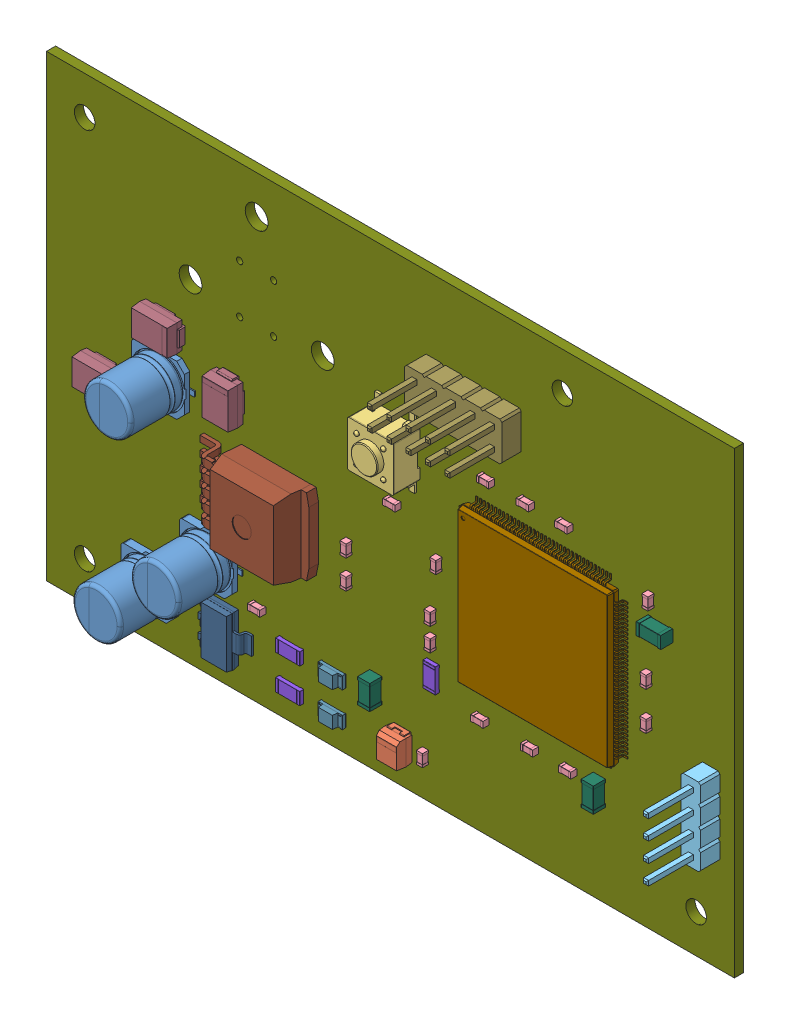
SolidWorks assembly PUTM-G-TM-PCB, configuration Domyślna. Lengths in mm.
Overall size (90 60 11.59).
104 component instances, 17 part files, 0 mates.
Components (placement in the parent):
- TC.step-1: TC.step [Domyślna] at origin size (90 60 11.59)
  - CP_Elec_6.3x7.7.step-1: CP_Elec_6.3x7.7.step [Domyślna] at (126.76 -92.79 1.25) x (-1 0 0) z (0 0 1) size (8.61 8.6 7.7)
    - SOLID.step-1: SOLID.step [Domyślna] at origin size (8.61 8.6 7.7)
  - CP_EIA-3528-21_Kemet-B.step-1: CP_EIA-3528-21_Kemet-B.step [Domyślna] at (159.142 -94.9444 1.25) x (0 -1 0) z (0 0 1) size (3.5 2.8 2.1)
    - SOLID-0.step-1: SOLID-0.step [Domyślna] at origin size (3.5 2.8 2.1)
  - SW_SPST_PTS645.step-1: SW_SPST_PTS645.step [Domyślna] at (158.392 -61.1944 1.25) x (0 -1 0) z (0 0 1) size (9 6 4.3)
    - SOLID-1.step-1: SOLID-1.step [Domyślna] at origin size (9 6 4.3)
  - C_0603_1608Metric.step-1: C_0603_1608Metric.step [Domyślna] at (158.142 -68.1944 1.25) x (-1 0 0) z (0 0 1) size (1.6 0.8 0.8)
    - SOLID-2.step-1: SOLID-2.step [Domyślna] at origin size (1.6 0.8 0.8)
  - PinHeader_1x04_P2.54mm_Vertical.step-1: PinHeader_1x04_P2.54mm_Vertical.step [Domyślna] at (199.392 -86.4444 1.25) x (-1 0 0) z (0 0 1) size (2.54 10.16 11.54)
    - SOLID-3.step-1: SOLID-3.step [Domyślna] at origin size (2.54 10.16 11.54)
  - SOIC-8_3.9x4.9mm_P1.27mm.step-1: SOIC-8_3.9x4.9mm_P1.27mm.step [Domyślna] at (160.892 -62.4444 -0.05) x (-1 0 0) z (0 0 -1) size (6 4.9 1.75)
    - SOLID-4.step-1: SOLID-4.step [Domyślna] at origin size (6 4.9 1.75)
  - TSOT-23.step-1: TSOT-23.step [Domyślna] at (151.892 -62.4444 -0.05) x (-1 0 0) z (0 0 -1) size (2.8 2.9 0.95)
    - SOLID-5.step-1: SOLID-5.step [Domyślna] at origin size (2.8 2.9 0.95)
  - R_1206_3216Metric.step-1: R_1206_3216Metric.step [Domyślna] at (145.892 -62.5444 -0.05) x (0 -1 0) z (0 0 -1) size (3.2 1.6 0.55)
    - SOLID-6.step-1: SOLID-6.step [Domyślna] at origin size (3.2 1.6 0.55)
  - LQFP-144_20x20mm_P0.5mm.step-1: LQFP-144_20x20mm_P0.5mm.step [Domyślna] at (177.642 -73.1944 1.25) size (22 22 1.5)
    - SOLID-7.step-1: SOLID-7.step [Domyślna] at origin size (22 22 1.5)
  - R_1206_3216Metric.step-2: R_1206_3216Metric.step [Domyślna] at (199.642 -64.9444 -0.05) x (-1 0 0) z (0 0 -1) size (3.2 1.6 0.55)
    - SOLID-6.step-1: SOLID-6.step [Domyślna] at origin size (3.2 1.6 0.55)
  - R_1206_3216Metric.step-3: R_1206_3216Metric.step [Domyślna] at (199.642 -67.9444 -0.05) x (-1 0 0) z (0 0 -1) size (3.2 1.6 0.55)
    - SOLID-6.step-1: SOLID-6.step [Domyślna] at origin size (3.2 1.6 0.55)
  - R_1206_3216Metric.step-4: R_1206_3216Metric.step [Domyślna] at (191.392 -56.6944 -0.05) x (-1 0 0) z (0 0 -1) size (3.2 1.6 0.55)
    - SOLID-6.step-1: SOLID-6.step [Domyślna] at origin size (3.2 1.6 0.55)
  - R_1206_3216Metric.step-5: R_1206_3216Metric.step [Domyślna] at (191.392 -47.6944 -0.05) x (-1 0 0) z (0 0 -1) size (3.2 1.6 0.55)
    - SOLID-6.step-1: SOLID-6.step [Domyślna] at origin size (3.2 1.6 0.55)
  - R_1206_3216Metric.step-6: R_1206_3216Metric.step [Domyślna] at (191.392 -50.6944 -0.05) x (-1 0 0) z (0 0 -1) size (3.2 1.6 0.55)
    - SOLID-6.step-1: SOLID-6.step [Domyślna] at origin size (3.2 1.6 0.55)
  - R_1206_3216Metric.step-7: R_1206_3216Metric.step [Domyślna] at (191.392 -53.6944 -0.05) x (-1 0 0) z (0 0 -1) size (3.2 1.6 0.55)
    - SOLID-6.step-1: SOLID-6.step [Domyślna] at origin size (3.2 1.6 0.55)
  - SOT-223.step-1: SOT-223.step [Domyślna] at (136.142 -93.6944 1.25) size (7 6.5 1.7)
    - SOLID-8.step-1: SOLID-8.step [Domyślna] at origin size (7 6.5 1.7)
  - TO-263-5_TabPin3.step-1: TO-263-5_TabPin3.step [Domyślna] at (140.642 -76.6944 1.25) size (15 10 4.42)
    - SOLID-9.step-1: SOLID-9.step [Domyślna] at origin size (15 10 4.42)
  - R_1206_3216Metric.step-8: R_1206_3216Metric.step [Domyślna] at (144.642 -96.1944 1.25) size (3.2 1.6 0.55)
    - SOLID-6.step-1: SOLID-6.step [Domyślna] at origin size (3.2 1.6 0.55)
  - R_1206_3216Metric.step-9: R_1206_3216Metric.step [Domyślna] at (144.642 -91.6944 1.25) x (-1 0 0) z (0 0 1) size (3.2 1.6 0.55)
    - SOLID-6.step-1: SOLID-6.step [Domyślna] at origin size (3.2 1.6 0.55)
  - R_1206_3216Metric.step-10: R_1206_3216Metric.step [Domyślna] at (183.892 -59.6944 -0.05) x (1 0 0) z (0 0 -1) size (3.2 1.6 0.55)
    - SOLID-6.step-1: SOLID-6.step [Domyślna] at origin size (3.2 1.6 0.55)
  - R_1206_3216Metric.step-11: R_1206_3216Metric.step [Domyślna] at (163.142 -85.3444 1.25) x (0 -1 0) z (0 0 1) size (3.2 1.6 0.55)
    - SOLID-6.step-1: SOLID-6.step [Domyślna] at origin size (3.2 1.6 0.55)
  - PinHeader_2x05_P2.54mm_Vertical.step-1: PinHeader_2x05_P2.54mm_Vertical.step [Domyślna] at (173.392 -50.6944 1.25) x (0 -1 0) z (0 0 1) size (5.08 12.7 11.54)
    - SOLID-10.step-1: SOLID-10.step [Domyślna] at origin size (5.08 12.7 11.54)
  - microSD_HC_Hirose_DM3D-SF.step-1: microSD_HC_Hirose_DM3D-SF.step [Domyślna] at (195.892 -52.9444 1.25) x (0 1 0) z (0 0 1)
    - SOLID-11.step-1: SOLID-11.step [Domyślna] at origin
  - D_SMB.step-1: D_SMB.step [Domyślna] at (120.392 -72.4444 1.25) x (-1 0 0) z (0 0 1) size (5.3 3.55 2.15)
    - SOLID-12.step-1: SOLID-12.step [Domyślna] at origin size (5.3 3.55 2.15)
  - LED_1206_3216Metric.step-1: LED_1206_3216Metric.step [Domyślna] at (150.142 -96.1944 1.25) x (-1 0 0) z (0 0 1) size (3.2 1.6 1.1)
    - SOLID-13.step-1: SOLID-13.step [Domyślna] at origin size (3.2 1.6 1.1)
  - LED_1206_3216Metric.step-2: LED_1206_3216Metric.step [Domyślna] at (150.142 -91.6944 1.25) x (-1 0 0) z (0 0 1) size (3.2 1.6 1.1)
    - SOLID-13.step-1: SOLID-13.step [Domyślna] at origin size (3.2 1.6 1.1)
  - D_SMB.step-2: D_SMB.step [Domyślna] at (136.75 -66.75 1.25) x (0 -1 0) z (0 0 1) size (5.3 3.55 2.15)
    - SOLID-12.step-1: SOLID-12.step [Domyślna] at origin size (5.3 3.55 2.15)
  - D_SMB.step-3: D_SMB.step [Domyślna] at (128.142 -63 1.25) x (-1 0 0) z (0 0 1) size (5.3 3.55 2.15)
    - SOLID-12.step-1: SOLID-12.step [Domyślna] at origin size (5.3 3.55 2.15)
  - C_0603_1608Metric.step-2: C_0603_1608Metric.step [Domyślna] at (162.142 -94.9444 1.25) x (0 -1 0) z (0 0 1) size (1.6 0.8 0.8)
    - SOLID-2.step-1: SOLID-2.step [Domyślna] at origin size (1.6 0.8 0.8)
  - C_0603_1608Metric.step-3: C_0603_1608Metric.step [Domyślna] at (191.642 -62.4444 1.25) x (0 1 0) z (0 0 1) size (1.6 0.8 0.8)
    - SOLID-2.step-1: SOLID-2.step [Domyślna] at origin size (1.6 0.8 0.8)
  - CP_Elec_6.3x7.7.step-2: CP_Elec_6.3x7.7.step [Domyślna] at (134.392 -86.1944 1.25) x (-1 0 0) z (0 0 1) size (8.61 8.6 7.7)
    - SOLID.step-1: SOLID.step [Domyślna] at origin size (8.61 8.6 7.7)
  - C_0603_1608Metric.step-4: C_0603_1608Metric.step [Domyślna] at (191.392 -71.4444 1.25) x (0 1 0) z (0 0 1) size (1.6 0.8 0.8)
    - SOLID-2.step-1: SOLID-2.step [Domyślna] at origin size (1.6 0.8 0.8)
  - C_0603_1608Metric.step-5: C_0603_1608Metric.step [Domyślna] at (170.392 -59.4444 1.25) x (-1 0 0) z (0 0 1) size (1.6 0.8 0.8)
    - SOLID-2.step-1: SOLID-2.step [Domyślna] at origin size (1.6 0.8 0.8)
  - C_0603_1608Metric.step-6: C_0603_1608Metric.step [Domyślna] at (152.142 -79.9444 1.25) x (0 1 0) z (0 0 1) size (1.6 0.8 0.8)
    - SOLID-2.step-1: SOLID-2.step [Domyślna] at origin size (1.6 0.8 0.8)
  - C_0603_1608Metric.step-7: C_0603_1608Metric.step [Domyślna] at (152.142 -76.1944 1.25) x (0 1 0) z (0 0 1) size (1.6 0.8 0.8)
    - SOLID-2.step-1: SOLID-2.step [Domyślna] at origin size (1.6 0.8 0.8)
  - C_0603_1608Metric.step-8: C_0603_1608Metric.step [Domyślna] at (180.642 -59.4444 1.25) x (-1 0 0) z (0 0 1) size (1.6 0.8 0.8)
    - SOLID-2.step-1: SOLID-2.step [Domyślna] at origin size (1.6 0.8 0.8)
  - C_0603_1608Metric.step-9: C_0603_1608Metric.step [Domyślna] at (160.892 -66.4444 -0.05) x (1 0 0) z (0 0 -1) size (1.6 0.8 0.8)
    - SOLID-2.step-1: SOLID-2.step [Domyślna] at origin size (1.6 0.8 0.8)
  - C_0603_1608Metric.step-10: C_0603_1608Metric.step [Domyślna] at (169.642 -86.9444 1.25) size (1.6 0.8 0.8)
    - SOLID-2.step-1: SOLID-2.step [Domyślna] at origin size (1.6 0.8 0.8)
  - C_0603_1608Metric.step-11: C_0603_1608Metric.step [Domyślna] at (140.45 -88.95 1.25) x (-1 0 0) z (0 0 1) size (1.6 0.8 0.8)
    - SOLID-2.step-1: SOLID-2.step [Domyślna] at origin size (1.6 0.8 0.8)
  - C_0603_1608Metric.step-12: C_0603_1608Metric.step [Domyślna] at (175.6045 -59.4444 1.25) x (-1 0 0) z (0 0 1) size (1.6 0.8 0.8)
    - SOLID-2.step-1: SOLID-2.step [Domyślna] at origin size (1.6 0.8 0.8)
  - C_0603_1608Metric.step-13: C_0603_1608Metric.step [Domyślna] at (176.142 -86.9444 1.25) size (1.6 0.8 0.8)
    - SOLID-2.step-1: SOLID-2.step [Domyślna] at origin size (1.6 0.8 0.8)
  - CP_Elec_6.3x7.7.step-3: CP_Elec_6.3x7.7.step [Domyślna] at (128.142 -69 1.25) x (-1 0 0) z (0 0 1) size (8.61 8.6 7.7)
    - SOLID.step-1: SOLID.step [Domyślna] at origin size (8.61 8.6 7.7)
  - C_0603_1608Metric.step-14: C_0603_1608Metric.step [Domyślna] at (163.142 -78.4444 1.25) x (0 1 0) z (0 0 1) size (1.6 0.8 0.8)
    - SOLID-2.step-1: SOLID-2.step [Domyślna] at origin size (1.6 0.8 0.8)
  - C_0603_1608Metric.step-15: C_0603_1608Metric.step [Domyślna] at (191.392 -76.4444 1.25) x (0 1 0) z (0 0 1) size (1.6 0.8 0.8)
    - SOLID-2.step-1: SOLID-2.step [Domyślna] at origin size (1.6 0.8 0.8)
  - C_0603_1608Metric.step-16: C_0603_1608Metric.step [Domyślna] at (181.142 -86.9444 1.25) size (1.6 0.8 0.8)
    - SOLID-2.step-1: SOLID-2.step [Domyślna] at origin size (1.6 0.8 0.8)
  - C_1206_3216Metric.step-1: C_1206_3216Metric.step [Domyślna] at (155.642 -90.4444 1.25) x (0 1 0) z (0 0 1) size (3.2 1.6 1.6)
    - SOLID-14.step-1: SOLID-14.step [Domyślna] at origin size (3.2 1.6 1.6)
  - C_0603_1608Metric.step-17: C_0603_1608Metric.step [Domyślna] at (163.892 -72.1944 1.25) x (0 -1 0) z (0 0 1) size (1.6 0.8 0.8)
    - SOLID-2.step-1: SOLID-2.step [Domyślna] at origin size (1.6 0.8 0.8)
  - C_0603_1608Metric.step-18: C_0603_1608Metric.step [Domyślna] at (163.142 -81.4444 1.25) x (0 -1 0) z (0 0 1) size (1.6 0.8 0.8)
    - SOLID-2.step-1: SOLID-2.step [Domyślna] at origin size (1.6 0.8 0.8)
  - R_1206_3216Metric.step-12: R_1206_3216Metric.step [Domyślna] at (165.76 -46.2775 -0.05) x (0 1 0) z (0 0 -1) size (3.2 1.6 0.55)
    - SOLID-6.step-1: SOLID-6.step [Domyślna] at origin size (3.2 1.6 0.55)
  - C_1206_3216Metric.step-2: C_1206_3216Metric.step [Domyślna] at (184.892 -87.4444 1.25) x (0 1 0) z (0 0 1) size (3.2 1.6 1.6)
    - SOLID-14.step-1: SOLID-14.step [Domyślna] at origin size (3.2 1.6 1.6)
  - C_1206_3216Metric.step-3: C_1206_3216Metric.step [Domyślna] at (192.892 -65.1944 1.25) x (-1 0 0) z (0 0 1) size (3.2 1.6 1.6)
    - SOLID-14.step-1: SOLID-14.step [Domyślna] at origin size (3.2 1.6 1.6)
  - COMPOUND.step-1: COMPOUND.step [Domyślna] at origin size (90 60 1.2)
